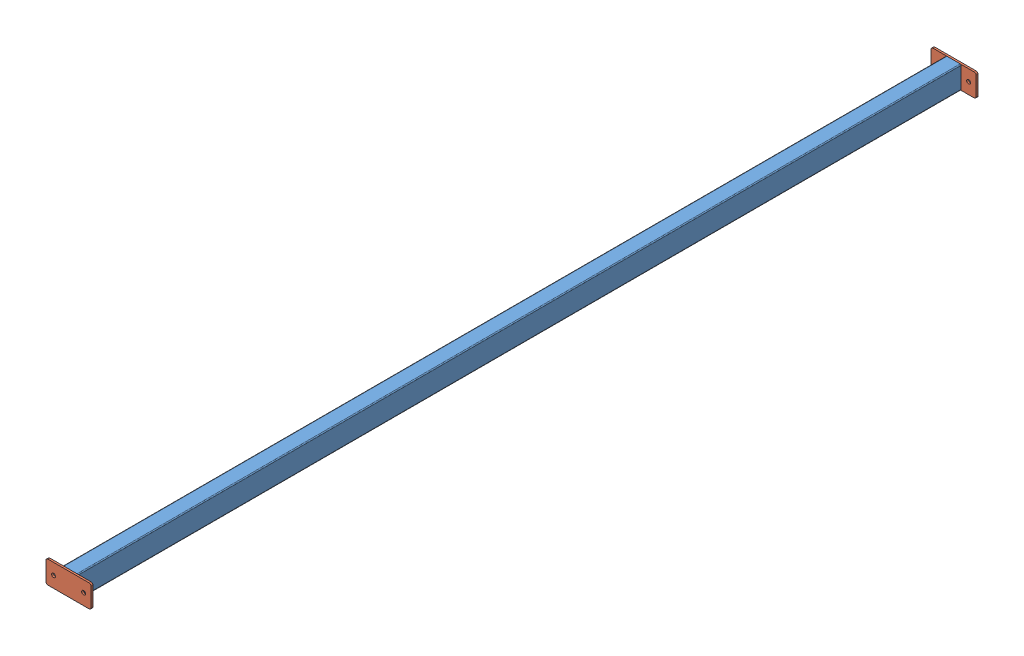
SolidWorks assembly front cross bar, configuration Default. Lengths in mm.
Overall size (152.4 76.2 2997.2).
3 component instances, 2 part files, 6 mates.
Components (placement in the parent):
- outer cross bar-1: outer cross bar [Default] at origin size (50.8 76.2 2984.5)
- front cross mount-1: front cross mount [Default] at (0 0 1492.25) x (0 1 0) z (0 0 1) size (76.2 152.4 6.35)
- front cross mount-2: front cross mount [Default] at (0 0 -1498.6) x (0 -1 0) z (0 0 1) size (76.2 152.4 6.35)
Mates (geometry in assembly coordinates):
- Coincident1: coincident anti-aligned: plane of front cross mount-1; plane of assembly through (0 0 0) normal (1 0 0)
- Coincident2: coincident anti-aligned: plane of outer cross bar-1 through (-22.225 -34.925 1492.25) normal (0 0 1); plane of front cross mount-1 through (-69.85 -31.75 1492.25) normal (0 0 -1)
- Coincident3: coincident aligned: plane of front cross mount-1; plane of assembly through (0 0 0) normal (0 1 0)
- Coincident4: coincident anti-aligned: plane of front cross mount-2; plane of assembly through (0 0 0) normal (0 1 0)
- Coincident5: coincident aligned: plane of front cross mount-2; plane of assembly through (0 0 0) normal (1 0 0)
- Coincident6: coincident anti-aligned: plane of outer cross bar-1 through (-22.225 -34.925 -1492.25) normal (0 0 -1); plane of front cross mount-2 through (69.85 31.75 -1492.25) normal (0 0 1)
